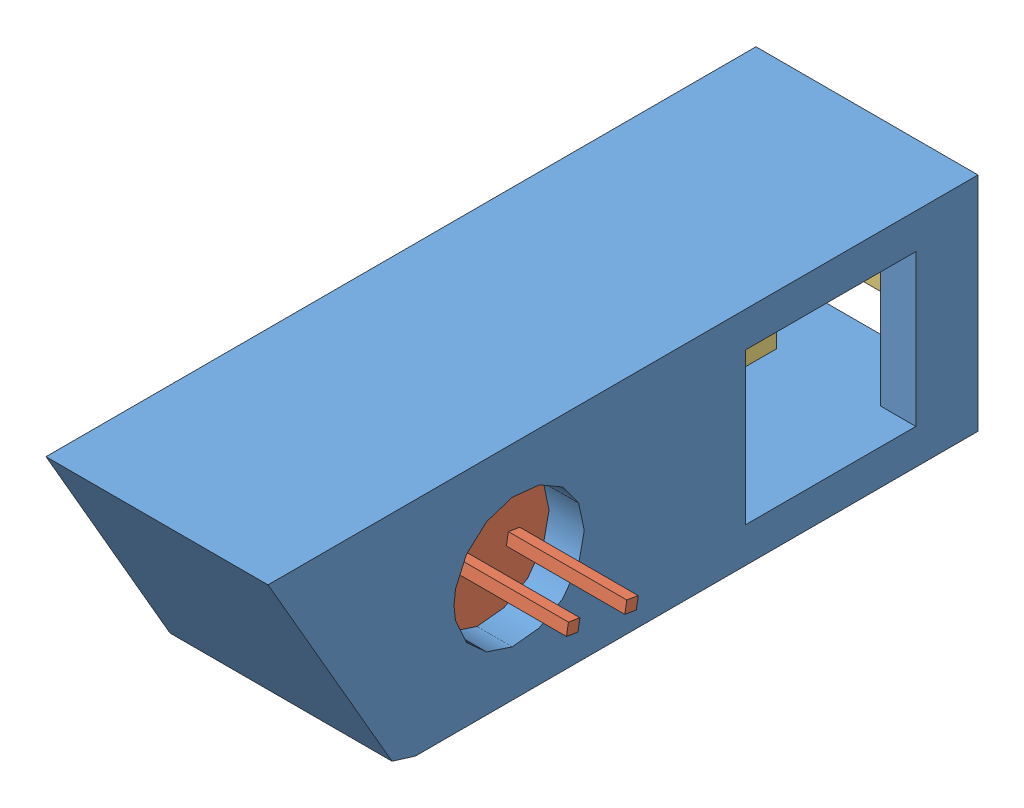
SolidWorks assembly BOM, Left Side TOP ASSY, configuration Default. Lengths in mm.
Overall size (14.59 9.52 32.19).
3 component instances, 3 part files, 4 mates.
Components (placement in the parent):
- MOUNTING BLOCK, COLOR SENSOR-1: MOUNTING BLOCK, COLOR SENSOR [Default] at (-9.0558 0.9508 4.1327) size (9.53 9.53 30.46)
- SENSOR, TSAL6200-1: SENSOR, TSAL6200 [Default] at (-12.3141 5.7133 11.7527) x (0 0.169363 0.985554) z (-1 0 0) size (5.39 5.8 14.08)
- SENSOR, VISHAY TSOP4838-1: SENSOR, VISHAY TSOP4838 [Default] at (-11.8683 5.7133 -1.4283) x (0 0 1) z (-1 0 0) size (11.71 6 6.24)
Mates (geometry in assembly coordinates):
- Concentric1: concentric anti-aligned: cylinder of MOUNTING BLOCK, COLOR SENSOR-1 through (-13.8183 5.7133 11.7527) axis (1 0 0) radius 2.794; cylinder of SENSOR, TSAL6200-1 through (-14.8041 5.7133 11.7527) axis (-1 0 0) radius 2.49
- Width1: width: plane of MOUNTING BLOCK, COLOR SENSOR-1 through (-13.8183 8.9613 2.0467) normal (0 -1 0); plane of MOUNTING BLOCK, COLOR SENSOR-1 through (-13.8183 2.4653 2.0467) normal (0 1 0); plane of SENSOR, VISHAY TSOP4838-1 through (-13.8183 8.7133 -4.9033) normal (0 1 0); plane of SENSOR, VISHAY TSOP4838-1 through (-13.8183 2.7133 -4.9033) normal (0 -1 0)
- Coincident3: coincident aligned: plane of MOUNTING BLOCK, COLOR SENSOR-1 through (-13.8183 10.4758 16.1977) normal (-1 0 0); plane of SENSOR, VISHAY TSOP4838-1 through (-13.8183 8.7133 2.0467) normal (-1 0 0)
- Coincident4: coincident anti-aligned: plane of MOUNTING BLOCK, COLOR SENSOR-1 through (-13.8183 8.9613 2.0467) normal (0 0 -1); plane of SENSOR, VISHAY TSOP4838-1 through (-13.8183 2.7133 2.0467) normal (0 0 1)
